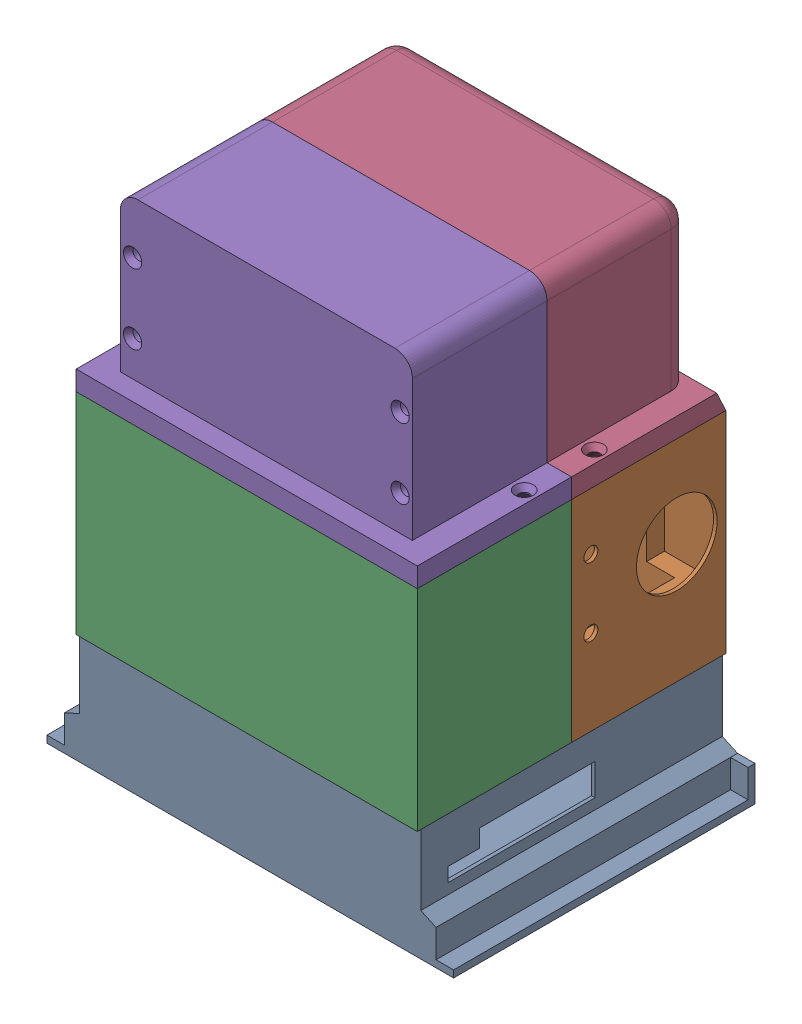
SolidWorks assembly 小对立, configuration 默认. Lengths in mm.
Overall size (116 142.6 88).
5 component instances, 5 part files, 11 mates.
Components (placement in the parent):
- deskGPT底座-stm32-1: deskGPT底座-stm32 [默认] at (-54.1326 -16.7006 0) size (116 32 86)
- deskGPT中间壳-2: deskGPT中间壳 [默认] at (-54.1326 15.2994 0) size (97.3 60 54)
- deskGPT中间壳2-2: deskGPT中间壳2 [默认] at (44.5174 15.2994 -40) x (-1 0 0) z (0 0 -1) size (97.3 60.02 44)
- deskGPT头-oled-part1-3: deskGPT头-oled-part1 [默认] at (-52.7826 75.2994 -84) size (97.3 50.73 44)
- deskGPT头-part2-2: deskGPT头-part2 [默认] at (44.5174 75.2994 4) x (-1 0 0) z (0 0 -1) size (97.3 50.72 44.05)
Mates (geometry in assembly coordinates):
- 同心1: concentric aligned: circle of deskGPT底座-stm32-1; circle of deskGPT中间壳-2
- 同心2: concentric anti-aligned: cylinder of deskGPT底座-stm32-1 through (40.5174 15.2994 -80) axis (0 -1 0) radius 1.6; cylinder of deskGPT中间壳-2 through (40.5174 75.2994 -80) axis (0 1 0) radius 1.7
- 重合1: coincident anti-aligned: plane of deskGPT底座-stm32-1 through (-54.1326 15.2994 0) normal (0 1 0); plane of deskGPT中间壳-2 through (-54.1326 15.2994 0) normal (0 -1 0)
- 重合2: coincident anti-aligned: plane of deskGPT中间壳-2 through (-47.7826 70.2994 -30) normal (1 0 0); plane of deskGPT中间壳2-2 through (-47.7826 70.2994 -30) normal (-1 0 0)
- 重合3: coincident anti-aligned: plane of deskGPT中间壳-2 through (-49.7826 70.2994 -30) normal (0 1 0); plane of deskGPT中间壳2-2 through (-47.7826 70.2994 -30) normal (0 -1 0)
- 重合4: coincident anti-aligned: plane of deskGPT中间壳-2 through (-54.1326 15.2994 -30) normal (0 0 1); plane of deskGPT中间壳2-2 through (44.5174 15.2994 -30) normal (0 0 -1)
- 同心10: concentric anti-aligned: cylinder of deskGPT中间壳-2 through (-49.2826 70.2994 -50) axis (0 1 0) radius 1.6; circle of deskGPT头-oled-part1-3
- 重合12: coincident aligned: line of deskGPT中间壳-2 through (44.5174 75.2994 -84) axis (-1 0 0); line of deskGPT头-oled-part1-3 through (44.5174 75.2994 -84) axis (-1 0 0)
- 同心11: concentric aligned: circle of deskGPT头-oled-part1-3; cylinder of deskGPT头-part2-2 through (-42.2826 110.8994 -3.3) axis (0 0 1) radius 1.6
- 同心12: concentric anti-aligned: circle of deskGPT头-oled-part1-3; circle of deskGPT头-part2-2
- 重合13: coincident anti-aligned: plane of deskGPT头-oled-part1-3 through (30.5174 80.8994 -40) normal (0 0 1); plane of deskGPT头-part2-2 through (-38.7826 80.8994 -40) normal (0 0 -1)
